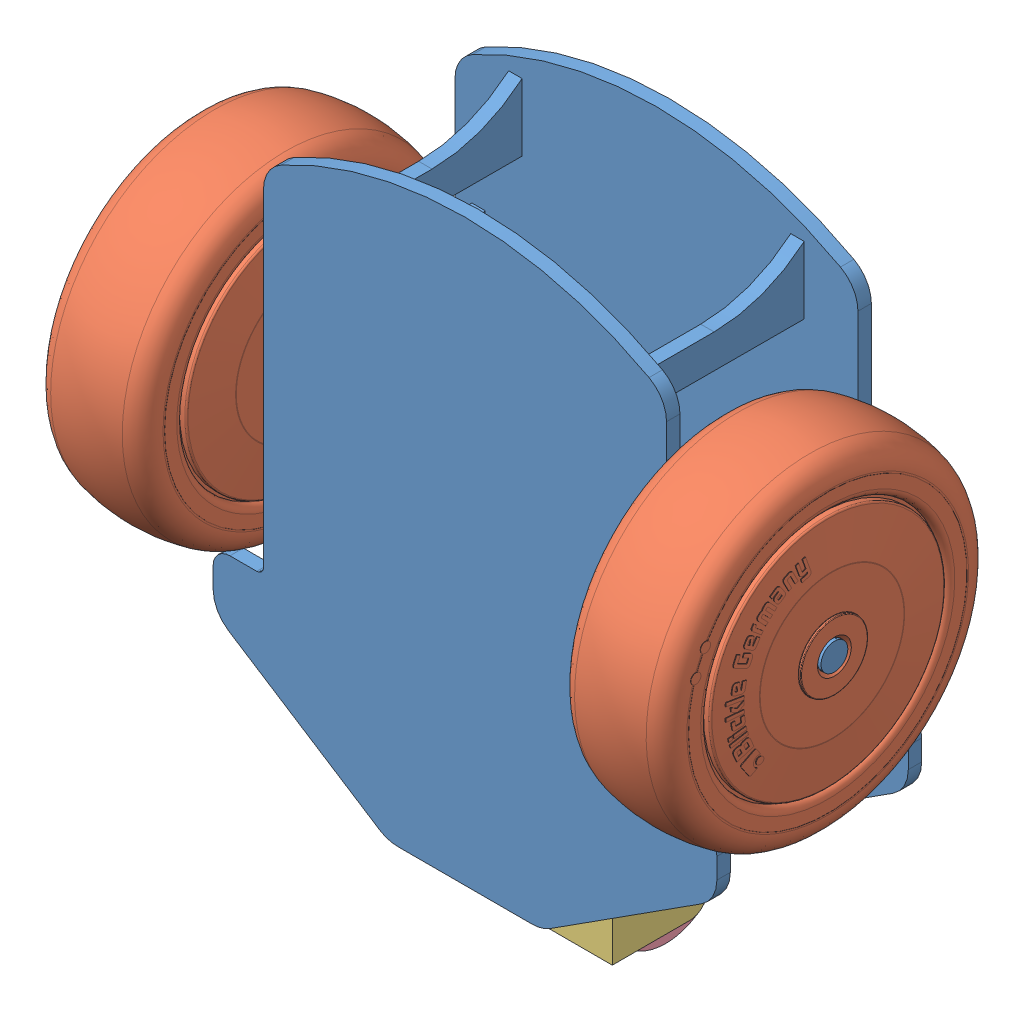
SolidWorks assembly baqubot_3, configuration Default. Lengths in mm.
Overall size (192 209.46 129.73).
5 component instances, 4 part files, 0 mates.
Components (placement in the parent):
- Base_2-1: Base_2 [Default] at (0 0 -47) x (-1 0 0) z (0 0 1) size (192 172.34 61)
- blickle_846910-1: blickle_846910 [Default] at (-78 0 0) x (-1 0 0) z (0 0 1) size (36 102.64 102.64)
- blickle_846910-2: blickle_846910 [Default] at (78 0 0) x (1 0 0) z (0 0.314911 0.949121) size (36 102.64 102.64)
- Front_Fork-1: Front_Fork [Default] at (0 -115 -32.5028) size (35 45 31.14)
- blickle_227934-1: blickle_227934 [Default] at (0 -115 -32.5028) x (-1 0 0) z (0 0.283508 0.95897) size (30 35.59 35.59)
